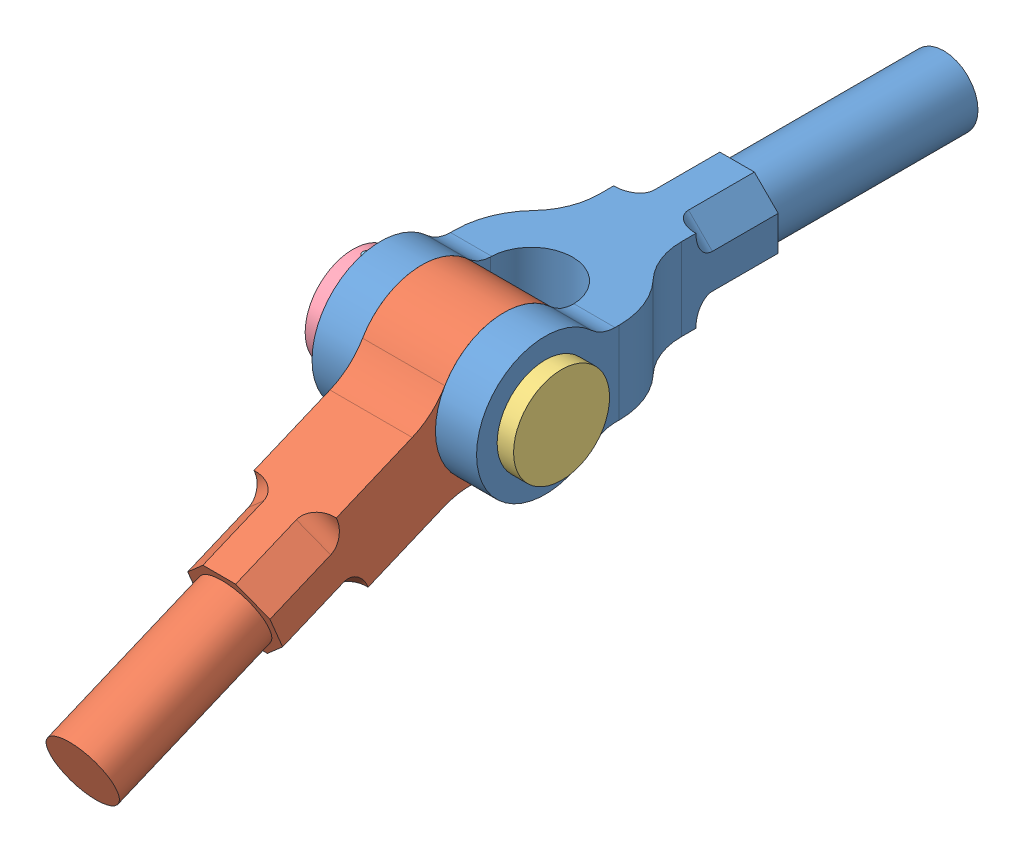
SolidWorks assembly knucle joint assembly, configuration Default. Lengths in mm.
Overall size (1570 2275.32 6472.14).
5 component instances, 5 part files, 8 mates.
Components (placement in the parent):
- fork_end-1: fork_end [Default] at (2468.5322 1687.8146 4816.7542) size (1200 1000 4007)
- eye end-2: eye end [Default] at (2168.5322 2187.8146 4316.7542) x (0 -0.385963 0.922514) z (-1 0 0) size (3505 1000 600)
- knuckle pin-1: knuckle pin [Default] at (1018.5322 2187.8146 4316.7542) x (-1 0 0) z (0 0 1) size (1570 700 700)
- collar-2: collar [Default] at (1068.5322 2187.8146 4316.7542) x (0 0 -1) z (1 0 0) size (700 700 200)
- taper pin-3: taper pin [Default] at (1168.5322 1837.8146 4316.7542) size (60 720 60)
Mates (geometry in assembly coordinates):
- Concentric5: concentric anti-aligned: circle of fork_end-1; cylinder of eye end-2 through (1568.5322 2187.8146 4316.7542) axis (1 0 0) radius 250
- Coincident1: coincident aligned: circle of fork_end-1; circle of eye end-2
- Coincident2: coincident aligned: cylinder of eye end-2 through (1568.5322 2187.8146 4316.7542) axis (1 0 0) radius 250; circle of knuckle pin-1
- Coincident3: coincident anti-aligned: plane of fork_end-1 through (2468.5322 2687.8146 4816.7542) normal (1 0 0); plane of knuckle pin-1 through (2468.5322 1937.8146 4316.7542) normal (-1 0 0)
- Concentric8: concentric anti-aligned: cylinder of knuckle pin-1 through (2588.5322 2187.8146 4316.7542) axis (1 0 0) radius 250; cylinder of collar-2 through (1268.5322 2187.8146 4316.7542) axis (-1 0 0) radius 250
- Concentric9: concentric anti-aligned: cylinder of knuckle pin-1 through (1168.5322 2537.8146 4316.7542) axis (0 -1 0) radius 30; cylinder of collar-2 through (1168.5322 1837.8146 4316.7542) axis (0 1 0) radius 30
- Concentric10: concentric anti-aligned: cylinder of collar-2 through (1168.5322 1837.8146 4316.7542) axis (0 1 0) radius 30; cylinder of taper pin-3 through (1168.5322 2557.8146 4316.7542) axis (0 -1 0) radius 30
- Tangent3: tangent: curve of collar-2; circle of taper pin-3
